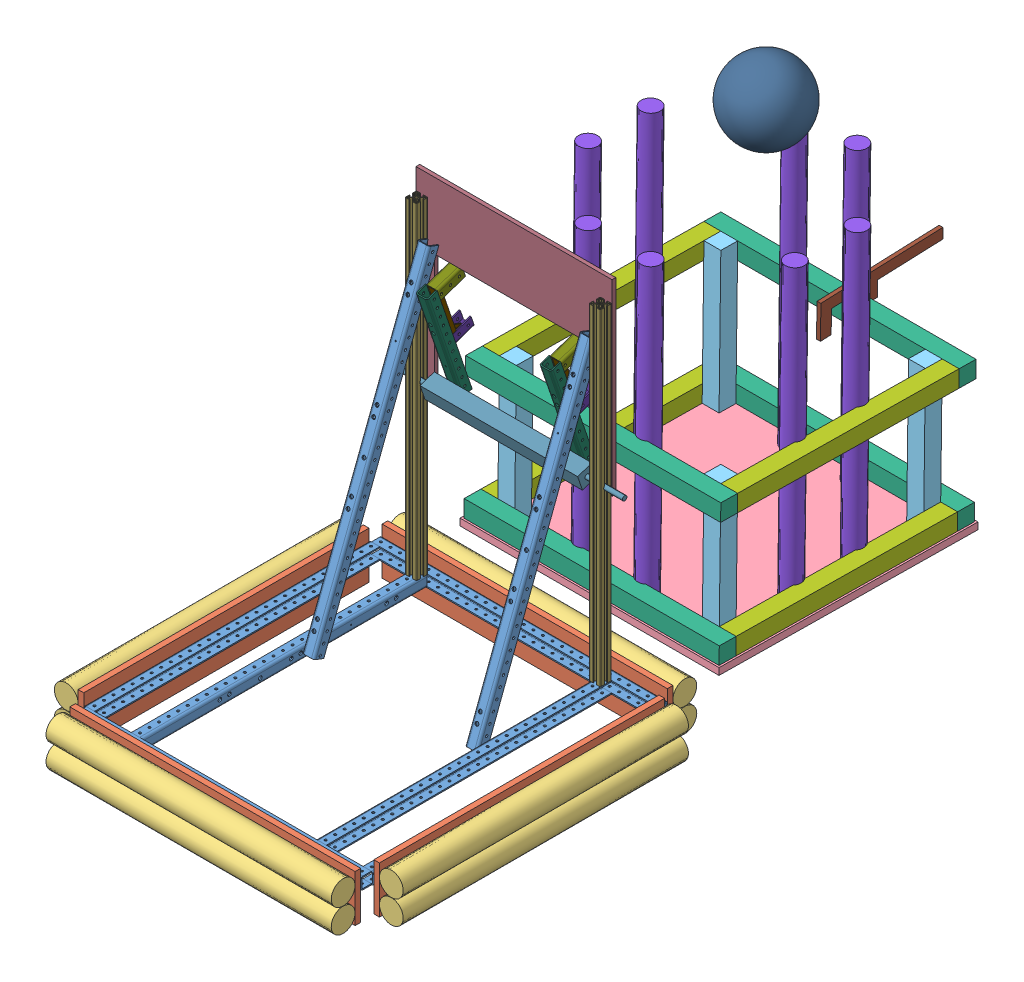
SolidWorks assembly Frame, configuration Default. Lengths in mm.
Overall size (953.99 1281.22 1971.68).
68 component instances, 19 part files, 32 mates.
Components (placement in the parent):
- User Library-C channel_-1: User Library-C channel_ [Default] at (-264.0117 419.6304 601.8198) size (760 31.75 28.57)
- User Library-C channel_-2: User Library-C channel_ [Default] at (612.1433 419.6304 689.3998) x (0 0 -1) z (1 0 0) size (760 31.75 28.57)
- User Library-C channel_-3: User Library-C channel_ [Default] at (463.4933 436.9764 689.3998) x (0 0 -1) z (-1 0 0) size (760 31.75 28.57)
- User Library-C channel_-4: User Library-C channel_ [Default] at (-154.2067 419.6304 -296.5602) x (0 0 1) z (-1 0 0) size (760 31.75 28.57)
- User Library-C channel_-5: User Library-C channel_ [Default] at (721.9484 419.6304 -208.9802) x (-1 0 0) z (0 0 -1) size (760 31.75 28.57)
- User Library-C channel_-6: User Library-C channel_ [Default] at (-5.5567 419.6304 689.3998) x (0 0 -1) z (1 0 0) size (760 31.75 28.57)
- Bumper-1: Bumper [Default] at (445.2766 -8.8291 392.6865) x (-1 0 0) z (0 0 -1) size (760 148.52 90.64)
  - Wood-1: Wood [Default] at (216.3082 417.3321 604.8417) size (760 125 15)
  - Foam-1: Foam [Default] at (-163.6918 447.7174 651.5917) x (0 -0.363902 0.931437) z (1 0 0) size (63.5 63.5 760)
  - Foam-3: Foam [Default] at (-163.6918 384.2174 651.5917) x (0 0.840256 0.542191) z (1 0 0) size (63.5 63.5 760)
- cart-1: cart [Default] at (273.0164 410.445 -685.3291) x (1 0 0) z (0 0.012665 0.99992) size (690 1266.2 920.66)
  - cart plate-1: cart plate [Default] at (0 27 0) size (690 18 690)
  - 4.5x4.5 l=40cm-1: 4.5x4.5 l=40cm [Default] at origin size (45 373 45)
  - 4.5x4.5 l=40cm-2: 4.5x4.5 l=40cm [Default] x (0 0 -1) z (1 0 0) size (45 373 45)
  - 4.5x4.5 l=40cm-3: 4.5x4.5 l=40cm [Default] x (-1 0 0) z (0 0 -1) size (45 373 45)
  - 4.5x4.5 l=40cm-4: 4.5x4.5 l=40cm [Default] x (0 0 1) z (-1 0 0) size (45 373 45)
  - 4.5x4.5 l=68cm-1: 4.5x4.5 l=68cm [Default] at origin size (680 45 45)
  - 4.5x4.5 l=59cm-1: 4.5x4.5 l=59cm [Default] at origin size (45 45 590)
  - 4.5x4.5 l=68cm-2: 4.5x4.5 l=68cm [Default] x (-1 0 0) z (0 0 -1) size (680 45 45)
  - 4.5x4.5 l=59cm-2: 4.5x4.5 l=59cm [Default] x (-1 0 0) z (0 0 -1) size (45 45 590)
  - 4.5x4.5 l=68cm-3: 4.5x4.5 l=68cm [Default] at (0 -328 0) size (680 45 45)
  - 4.5x4.5 l=59cm-3: 4.5x4.5 l=59cm [Default] at (0 -328 0) size (45 45 590)
  - 4.5x4.5 l=68cm-4: 4.5x4.5 l=68cm [Default] at (0 -328 0) x (-1 0 0) z (0 0 -1) size (680 45 45)
  - 4.5x4.5 l=59cm-4: 4.5x4.5 l=59cm [Default] at (0 -328 0) x (-1 0 0) z (0 0 -1) size (45 45 590)
  - pvc pipe l=80cm-1: pvc pipe l=80cm [Default] at origin size (50.8 773 50.8)
  - pvc pipe l=80cm-2: pvc pipe l=80cm [Default] at (0 0 166.667) size (50.8 773 50.8)
  - pvc pipe l=80cm-3: pvc pipe l=80cm [Default] x (0 0 -1) z (1 0 0) size (50.8 773 50.8)
  - pvc pipe l=80cm-4: pvc pipe l=80cm [Default] at (166.667 0 0) x (0 0 -1) z (1 0 0) size (50.8 773 50.8)
  - pvc pipe l=80cm-5: pvc pipe l=80cm [Default] x (-1 0 0) z (0 0 -1) size (50.8 773 50.8)
  - pvc pipe l=80cm-6: pvc pipe l=80cm [Default] at (0 0 -166.667) x (-1 0 0) z (0 0 -1) size (50.8 773 50.8)
  - pvc pipe l=80cm-7: pvc pipe l=80cm [Default] x (0 0 1) z (-1 0 0) size (50.8 773 50.8)
  - pvc pipe l=80cm-8: pvc pipe l=80cm [Default] at (-166.667 0 0) x (0 0 1) z (-1 0 0) size (50.8 773 50.8)
  - crazy wheel-1: crazy wheel [Default] at (185 27 -185) size (60 101 80)
  - crazy wheel-2: crazy wheel [Default] at (185 27 185) size (60 101 80)
  - crazy wheel-3: crazy wheel [Default] at (-185 27 -185) size (60 101 80)
  - crazy wheel-4: crazy wheel [Default] at (-185 27 185) size (60 101 80)
  - Ball-1: Ball [Default] at (140.5737 1092.1977 28.2994) size (200 200 200)
  - F hand-1: F hand [Default] at (19.9991 445.2193 -490.7705) x (0.050393 0 0.998729) z (-0.998729 0 0.050393) size (342.75 87.22 10)
- Handz-1: Handz [Default] at (871.8955 360.1229 416.4017) x (-1 0 0) z (0 0 -1) size (522.3 925.5 40)
  - 8020-30-3030-30-3030 X 4 M-1: 8020-30-3030-30-3030 X 4 M [Default] at (110.6415 -3045.9445 556.6015) size (30 870 30)
  - 8020-30-3030-30-3030 X 4 M-2: 8020-30-3030-30-3030 X 4 M [Default] at (600.5416 -3045.9445 556.6015) size (30 870 30)
  - Poygal-1: Poygal [Default] at (904.0582 509.5555 609.9819) x (0 0 -1) z (1 0 0) size (10 500 522.3)
- hands of Handz-1: hands of Handz [Default] at (228.9435 878.3581 -175.0963) x (-1 0 0) z (0 0.946509 0.322676) size (736.72 654.9 627.14)
  - F holder-1: F holder [Default] at origin size (620 192.99 40)
  - F-Hand Complete-1: F-Hand Complete [Default] at (-42.5204 176.6839 360.2114) x (-0.161759 -0.38426 -0.908944) z (-0.935098 -0.234623 0.265601) size (552.85 473.7 180)
    - C-base 34cm-1: C-base 34cm [Default] at (956.6526 -166.43 -81.5617) x (-0.908944 0.321368 0.265601) z (-0.38426 -0.892915 -0.234623) size (444.34 31.75 28.57)
    - C-channel6cm-1: C-channel6cm [Default] at (-132.7439 -581.215 -32.979) x (0.38426 0.892915 0.234623) z (-0.908944 0.321368 0.265601) size (444.34 31.75 28.57)
    - C-Channel 4cm-1: C-Channel 4cm [Default] at (-5.5514 -640.6374 -93.5688) x (0.38426 0.892915 0.234623) z (0.908944 -0.321368 -0.265601) size (444.34 31.75 28.57)
    - Holder-1: Holder [Default] at (208.6091 126.4129 137.339) x (-0.161759 0.315319 -0.935098) z (0.38426 0.892915 0.234623) size (31.8 150.5 40)
  - F-Hand Complete-2: F-Hand Complete [Default] at (287.0891 176.6839 360.2114) x (-0.161759 -0.38426 -0.908944) z (-0.935098 -0.234623 0.265601) size (552.85 473.7 180)
    - C-base 34cm-1: C-base 34cm [Default] at (956.6526 -166.43 -81.5617) x (-0.908944 0.321368 0.265601) z (-0.38426 -0.892915 -0.234623) size (444.34 31.75 28.57)
    - C-channel6cm-1: C-channel6cm [Default] at (-132.7439 -581.215 -32.979) x (0.38426 0.892915 0.234623) z (-0.908944 0.321368 0.265601) size (444.34 31.75 28.57)
    - C-Channel 4cm-1: C-Channel 4cm [Default] at (-5.5514 -640.6374 -93.5688) x (0.38426 0.892915 0.234623) z (0.908944 -0.321368 -0.265601) size (444.34 31.75 28.57)
    - Holder-1: Holder [Default] at (208.6091 126.4129 137.339) x (-0.161759 0.315319 -0.935098) z (0.38426 0.892915 0.234623) size (31.8 150.5 40)
- C channel 85cm-1: C channel 85cm [Default] at (453.1403 413.8026 149.4239) x (-0.001602 0.934593 -0.355716) z (0 0.355716 0.934594) size (858 31.75 28.57)
- C channel 85cm-2: C channel 85cm [Default] at (22.1414 413.7753 152.7057) x (0.001661 0.934593 -0.355716) z (0 0.355716 0.934594) size (858 31.75 28.57)
- Bumper-2: Bumper [Default] at (12.6601 -14.6329 0.1532) size (760 148.52 90.64)
  - Wood-1: Wood [Default] at (216.3082 417.3321 604.8417) size (760 125 15)
  - Foam-1: Foam [Default] at (-163.6918 447.7174 651.5917) x (0 -0.363902 0.931437) z (1 0 0) size (63.5 63.5 760)
  - Foam-3: Foam [Default] at (-163.6918 384.2174 651.5917) x (0 0.840256 0.542191) z (1 0 0) size (63.5 63.5 760)
- Bumper-3: Bumper [Default] at (10.4767 -5.9823 412.728) x (0 0 -1) z (1 0 0) size (760 148.52 90.64)
  - Wood-1: Wood [Default] at (216.3082 417.3321 604.8417) size (760 125 15)
  - Foam-1: Foam [Default] at (-163.6918 447.7174 651.5917) x (0 -0.363902 0.931437) z (1 0 0) size (63.5 63.5 760)
  - Foam-3: Foam [Default] at (-163.6918 384.2174 651.5917) x (0 0.840256 0.542191) z (1 0 0) size (63.5 63.5 760)
- Bumper-4: Bumper [Default] at (447.46 -7.1738 -19.8884) x (0 0 1) z (-1 0 0) size (760 148.52 90.64)
  - Wood-1: Wood [Default] at (216.3082 417.3321 604.8417) size (760 125 15)
  - Foam-1: Foam [Default] at (-163.6918 447.7174 651.5917) x (0 -0.363902 0.931437) z (1 0 0) size (63.5 63.5 760)
  - Foam-3: Foam [Default] at (-163.6918 384.2174 651.5917) x (0 0.840256 0.542191) z (1 0 0) size (63.5 63.5 760)
Mates (geometry in assembly coordinates):
- Distance3: distance = 155 mm anti-aligned: plane of User Library-C channel_-4 through (-157.3817 412.4284 576.4198) normal (-1 0 0); plane of User Library-C channel_-6 through (-2.3817 412.4284 -183.5802) normal (1 0 0)
- Coincident12: coincident anti-aligned: line of User Library-C channel_-1 through (608.9683 444.1784 576.4198) axis (-1 0 0); line of User Library-C channel_-3 through (466.6683 444.1784 576.4198) axis (1 0 0)
- Coincident13: coincident aligned: line of User Library-C channel_-3 through (488.8933 412.4284 -183.5802) axis (-1 0 0); line of User Library-C channel_-5 through (608.9683 412.4284 -183.5802) axis (-1 0 0)
- Distance4: distance = 155 mm anti-aligned: plane of User Library-C channel_-3 through (460.3183 444.1784 -183.5802) normal (-1 0 0); plane of User Library-C channel_-2 through (615.3183 412.4284 -183.5802) normal (1 0 0)
- Coincident20: coincident anti-aligned: plane of User Library-C channel_-5 through (-151.0317 412.4284 -212.1552) normal (0 0 -1); plane of Bumper-1/Wood-1 through (228.9683 408.5029 -212.1552) normal (0 0 1)
- Coincident21: coincident aligned: line of User Library-C channel_-5 through (-151.0317 418.7784 -212.1552) axis (0 1 0); line of Bumper-1/Wood-1 through (-151.0317 346.0029 -212.1552) axis (0 1 0)
- Distance of cart to bumper: distance = 50 mm anti-aligned: plane of cart-1/cart plate-1 through (-71.9836 441.8125 -340.6988) normal (0 0.012665 0.99992); cylinder of Bumper-1/Foam-1 through (-151.0317 438.8883 -258.9052) axis (1 0 0) radius 31.75
- Coincident108: coincident anti-aligned: point of User Library-C channel_-4; point of User Library-C channel_-5
- Coincident110: coincident: line of User Library-C channel_-1 through (-151.0317 412.4284 576.4198) axis (1 0 0); point of User Library-C channel_-6
- Coincident111: coincident: point of User Library-C channel_-1; point of User Library-C channel_-4
- Coincident114: coincident: point of User Library-C channel_-1; point of User Library-C channel_-2
- Coincident115: coincident: point of User Library-C channel_-2; line of User Library-C channel_-5 through (-151.0317 444.1784 -183.5802) axis (1 0 0)
- Coincident120: coincident anti-aligned: line of User Library-C channel_-6 through (-30.9567 444.1784 -183.5802) axis (0 0 1); line of Handz-1/8020-30-3030-30-3030 X 4 M-2 through (-30.9567 444.1784 -173.0802) axis (0 0 -1)
- Parallel2: parallel aligned: plane of User Library-C channel_-3 through (488.8933 444.1784 -183.5802) normal (1 0 0); plane of Handz-1/8020-30-3030-30-3030 X 4 M-1 through (488.9433 1314.1784 -155.5803) normal (1 0 0)
- Distance6: distance = 230 mm: point of hands of Handz-1/F holder-1; plane of Handz-1/8020-30-3030-30-3030 X 4 M-1 through (458.9435 1314.1784 -164.0802) normal (-1 0 0)
- Concentric2: concentric anti-aligned: cylinder of Handz-1/8020-30-3030-30-3030 X 4 M-2 through (-0.9568 897.2883 -168.6427) axis (-1 0 0) radius 6.1; cylinder of hands of Handz-1/F holder-1 through (-81.0565 897.2883 -168.6427) axis (1 0 0) radius 6
- Coincident128: coincident aligned: line of User Library-C channel_-5 through (-151.0317 444.1784 -183.5802) axis (1 0 0); line of User Library-C channel_-6 through (-30.9567 444.1784 -183.5802) axis (1 0 0)
- Coincident131: coincident: plane of User Library-C channel_-3 through (460.3183 444.1784 -183.5802) normal (-1 0 0); line of C channel 85cm-1 through (460.3183 426.6842 141.1239) axis (0 -0.355716 -0.934594)
- Coincident133: coincident: plane of Handz-1/8020-30-3030-30-3030 X 4 M-1 through (458.9435 1314.1784 -181.5802) normal (-1 0 0); point of C channel 85cm-1
- Coincident146: coincident: line of User Library-C channel_-3 through (460.3183 418.7784 -183.5802) axis (0 0 1); point of C channel 85cm-1
- Coincident147: coincident: line of Handz-1/8020-30-3030-30-3030 X 4 M-1 through (458.9435 1314.1784 -164.0802) axis (0 -1 0); point of C channel 85cm-1
- Coincident150: coincident anti-aligned: line of User Library-C channel_-6 through (-30.9567 444.1784 -183.5802) axis (1 0 0); line of Handz-1/8020-30-3030-30-3030 X 4 M-2 through (-20.4567 444.1784 -183.5802) axis (-1 0 0)
- Coincident151: coincident: line of Handz-1/8020-30-3030-30-3030 X 4 M-2 through (-0.9568 1314.1784 -181.5802) axis (0 -1 0); point of C channel 85cm-2
- Coincident153: coincident: line of User Library-C channel_-6 through (-2.3817 418.7784 576.4198) axis (0 0 -1); point of C channel 85cm-2
- Coincident155: coincident: plane of User Library-C channel_-6 through (-2.3817 412.4284 -183.5802) normal (1 0 0); line of C channel 85cm-2 through (-2.3817 418.7784 123.6239) axis (0 0.355716 0.934594)
- Parallel13: parallel aligned: line of C channel 85cm-1 through (427.1935 1220.6115 -184.8335) axis (0 0.355716 0.934594); line of C channel 85cm-2 through (30.7932 1220.6097 -181.5614) axis (0 0.355716 0.934594)
- Coincident163: coincident anti-aligned: plane of User Library-C channel_-4 through (-157.3817 412.4284 576.4198) normal (-1 0 0); plane of Bumper-4/Wood-1 through (-157.3817 410.1583 196.4198) normal (1 0 0)
- Coincident167: coincident aligned: line of User Library-C channel_-4 through (-157.3817 418.7784 576.4198) axis (0 1 0); line of Bumper-4/Wood-1 through (-157.3817 347.6583 576.4198) axis (0 1 0)
- Coincident169: coincident: plane of User Library-C channel_-1 through (608.9683 412.4284 604.9948) normal (0 0 1); plane of Bumper-2/Wood-1 through (228.9683 402.6992 604.9948) normal (0 0 -1)
- Coincident170: coincident aligned: line of User Library-C channel_-1 through (-151.0317 437.8284 604.9948) axis (0 -1 0); line of Bumper-2/Wood-1 through (-151.0317 465.1992 604.9948) axis (0 -1 0)
- Coincident171: coincident: plane of User Library-C channel_-2 through (615.3183 412.4284 -183.5802) normal (1 0 0); plane of Bumper-3/Wood-1 through (615.3183 411.3497 196.4198) normal (-1 0 0)
- Coincident172: coincident aligned: line of User Library-C channel_-2 through (615.3183 437.8284 576.4198) axis (0 -1 0); line of Bumper-3/Wood-1 through (615.3183 473.8497 576.4198) axis (0 -1 0)
